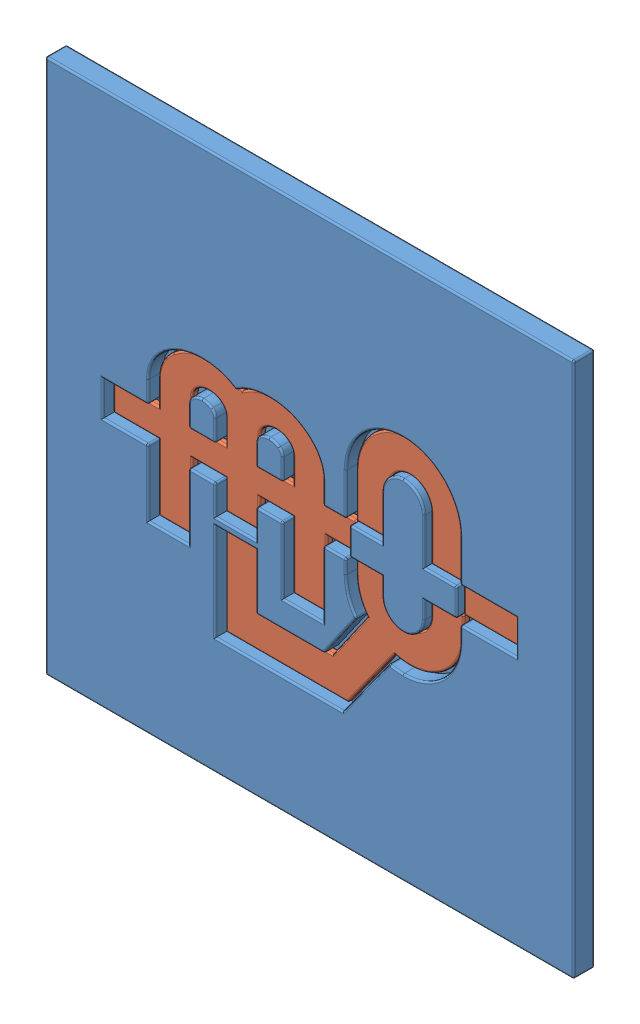
SolidWorks assembly Logo, configuration Valor predeterminado. Lengths in mm.
Overall size (75.8 76.8 3.26).
2 component instances, 2 part files, 3 mates.
Components (placement in the parent):
- Logo2-1: Logo2 [Valor predeterminado] at (-65.6652 33.3216 76.8) size (75.8 76.8 3.26)
- Logo1-1: Logo1 [Valor predeterminado] at (-65.6652 33.3216 77.8) size (58.35 37.81 1.42)
Mates (geometry in assembly coordinates):
- Distância1: distance = 0.5 mm anti-aligned: plane of Logo1-1 through (-61.4544 33.3216 78.8) normal (-1 0 0); plane of Logo2-1 through (-61.9544 33.3216 79.8) normal (1 0 0)
- Distância2: distance = 0.5 mm anti-aligned: plane of Logo2-1 through (-65.6714 4.4645 79.8) normal (-0.000215 -1 0); plane of Logo1-1 through (-65.6715 3.9645 78.8) normal (0.000215 1 0)
- Coincidente3: coincident anti-aligned: plane of Logo2-1 through (-65.6652 33.3216 77.8) normal (0 0 1); plane of Logo1-1 through (-66.0152 33.3217 77.8) normal (0 0 -1)
